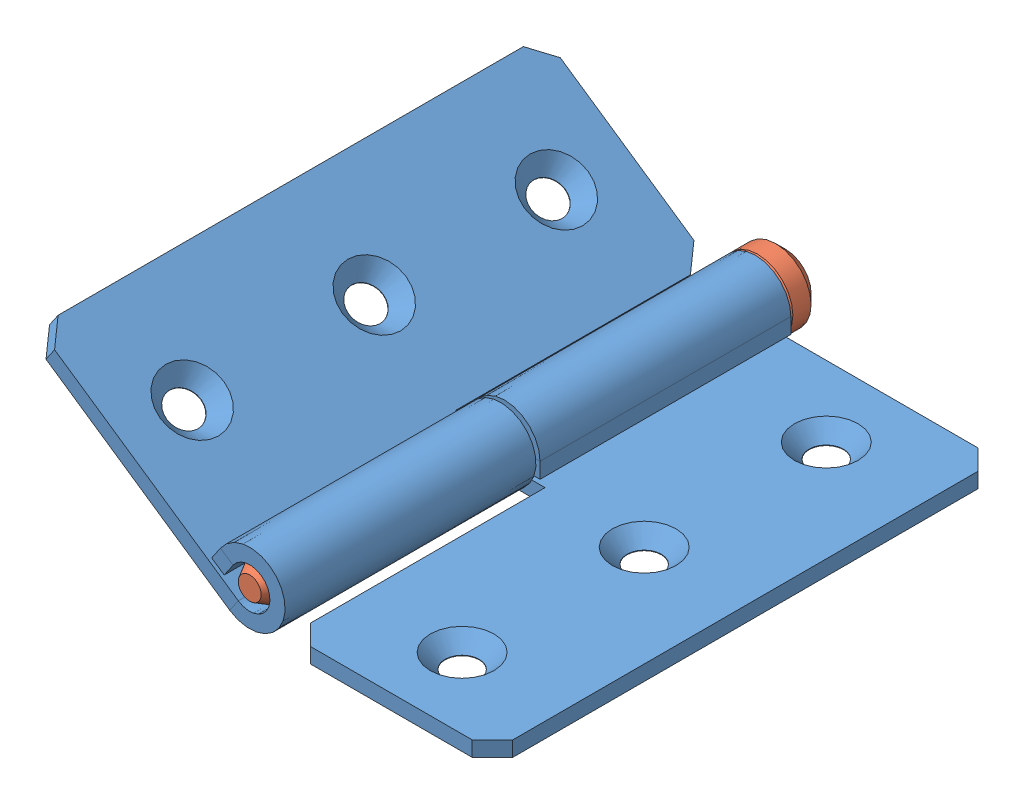
SolidWorks assembly Hinge, configuration Default. Lengths in mm.
Overall size (45.79 21.29 53).
3 component instances, 2 part files, 5 mates.
Components (placement in the parent):
- krilo 1-1: krilo 1 [Default] at origin size (27.5 7 50)
- krilo 1-2: krilo 1 [Default] at (-26.6878 8.2466 -50) x (-0.82568 0.564139 0) z (0 0 -1) size (27.5 7 50)
- Klin-1: Klin [Default] at (-14 2 0) size (7 7 53)
Mates (geometry in assembly coordinates):
- Coincident1: coordinate: point of krilo 1-1; point of assembly
- Concentric1: concentric: cylinder of krilo 1-1 through (-14 2 -9.5781) axis (0 0 -1) radius 3.5; cylinder of krilo 1-2 through (-14 2 -40.4219) axis (0 0 1) radius 3.5
- Coincident2: coincident: plane of krilo 1-1 through (-10 -1.5 0) normal (0 0 1); plane of krilo 1-2 through (-4.0021 -9.0699 0) normal (0 0 1)
- Concentric2: concentric: cylinder of krilo 1-1 through (-14 2 -9.5781) axis (0 0 -1) radius 2; cylinder of Klin-1 through (-14 2 0) axis (0 0 -1) radius 2
- Coincident3: coincident: plane of krilo 1-1 through (-14 2 -50) normal (0 0 -1); plane of Klin-1 through (-10.5 2 -50) normal (0 0 1)
